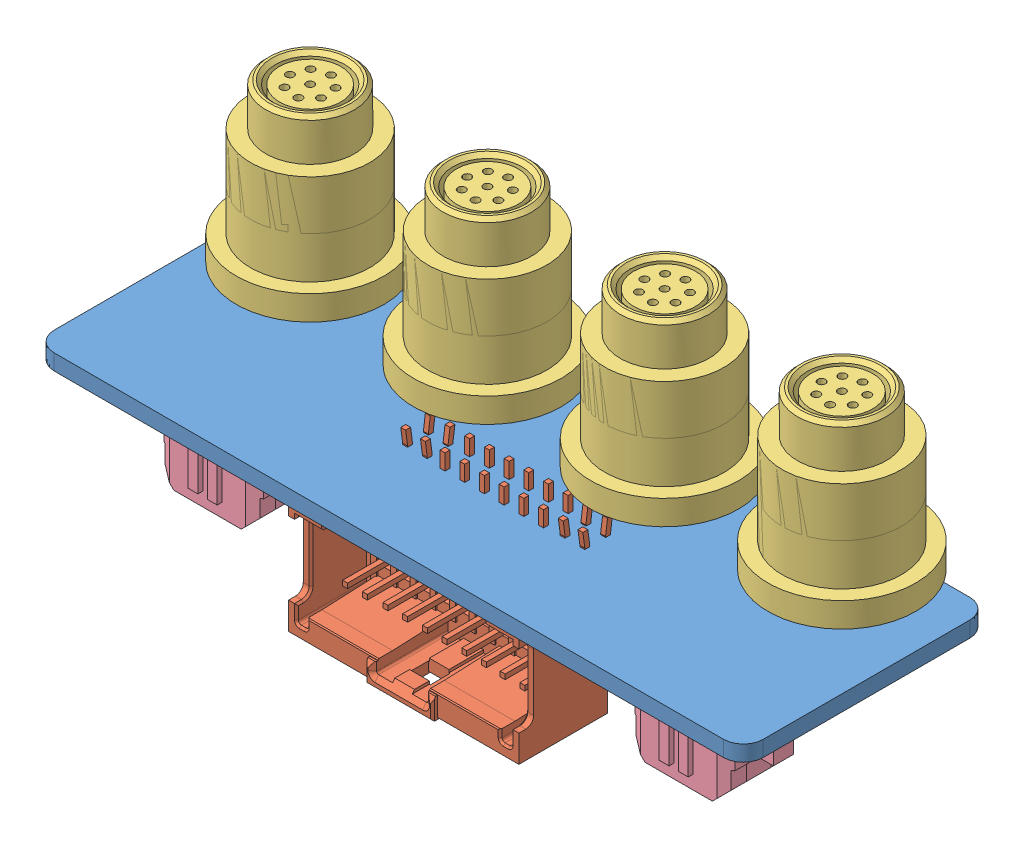
SolidWorks assembly Rear_MCN_BO, configuration Default. Lengths in mm.
Overall size (74.76 32.3 28.38).
8 component instances, 4 part files, 17 mates.
Components (placement in the parent):
- Rear_MCN_BO_PCB-1: Rear_MCN_BO_PCB [Default] at origin size (72 1.6 25)
- MicroClasp_20_RA-1: MicroClasp_20_RA [Default] at (37 -5.05 -7.5) x (-1 0 0) z (0 1 0) size (23.4 14.5 14.9)
- M8 Connector-1: M8 Connector [Default] at (10 20.6 -18) x (-0.837169 0 -0.546944) z (-0.546944 0 0.837169) size (15 22 15)
- M8 Connector-2: M8 Connector [Default] at (28 20.6 -18) x (-0.837169 0 -0.546944) z (-0.546944 0 0.837169) size (15 22 15)
- M8 Connector-3: M8 Connector [Default] at (46 20.6 -18) x (-0.837169 0 -0.546944) z (-0.546944 0 0.837169) size (15 22 15)
- M8 Connector-4: M8 Connector [Default] at (64 20.6 -18) x (-0.837169 0 -0.546944) z (-0.546944 0 0.837169) size (15 22 15)
- Molex MicroFit 4pos vertical header - 43045-0418-1: Molex MicroFit 4pos vertical header - 43045-0418 [Default] at (12.075 -4.96 -8.93) x (-1 0 0) z (0 -1 0) size (13.65 11.2 9.96)
- Molex MicroFit 4pos vertical header - 43045-0418-2: Molex MicroFit 4pos vertical header - 43045-0418 [Default] at (59.925 -4.96 -8.93) x (-1 0 0) z (0 -1 0) size (13.65 11.2 9.96)
Mates (geometry in assembly coordinates):
- Coincident1: coincident anti-aligned: plane of Rear_MCN_BO_PCB-1 through (0 0 0) normal (0 -1 0); plane of MicroClasp_20_RA-1 through (48.7 0 -0.5) normal (0 1 0)
- Coincident2: coincident aligned: plane of Rear_MCN_BO_PCB-1 through (0 1.6 0) normal (0 0 1); plane of MicroClasp_20_RA-1 through (40.425 -11.7 0) normal (0 0 1)
- Distance1: distance = 23.3 mm aligned: plane of MicroClasp_20_RA-1 through (48.7 -5.05 -7.5) normal (1 0 0); plane of Rear_MCN_BO_PCB-1 through (72 1.6 0) normal (1 0 0)
- Coincident3: coincident: plane of Rear_MCN_BO_PCB-1 through (0 1.6 0) normal (0 1 0); plane of M8 Connector-1 through (11.3056 1.6 -16.6473) normal (0 -1 0)
- Coincident4: coincident: plane of Rear_MCN_BO_PCB-1 through (0 1.6 0) normal (0 1 0); plane of M8 Connector-2 through (29.3056 1.6 -16.6473) normal (0 -1 0)
- Coincident5: coincident: plane of Rear_MCN_BO_PCB-1 through (0 1.6 0) normal (0 1 0); plane of M8 Connector-3 through (47.8716 1.6 -18.1774) normal (0 -1 0)
- Coincident6: coincident: plane of Rear_MCN_BO_PCB-1 through (0 1.6 0) normal (0 1 0); plane of M8 Connector-4 through (65.8716 1.6 -18.1774) normal (0 -1 0)
- Concentric3: concentric aligned: circle of Rear_MCN_BO_PCB-1; circle of M8 Connector-1
- Concentric4: concentric aligned: circle of Rear_MCN_BO_PCB-1; circle of M8 Connector-2
- Concentric5: concentric aligned: circle of Rear_MCN_BO_PCB-1; circle of M8 Connector-3
- Concentric6: concentric aligned: circle of Rear_MCN_BO_PCB-1; circle of M8 Connector-4
- Coincident9: coincident: plane of Rear_MCN_BO_PCB-1 through (0 0 0) normal (0 -1 0); plane of Molex MicroFit 4pos vertical header - 43045-0418-2 through (64.75 0 -5) normal (0 1 0)
- Coincident10: coincident: plane of Rear_MCN_BO_PCB-1 through (0 0 0) normal (0 -1 0); plane of Molex MicroFit 4pos vertical header - 43045-0418-1 through (16.9 0 -5) normal (0 1 0)
- Distance2: distance = 5.5 mm: plane of Molex MicroFit 4pos vertical header - 43045-0418-1 through (16.9 -9.91 -5.5) normal (0 0 1); plane of Rear_MCN_BO_PCB-1 through (0 1.6 0) normal (0 0 1)
- Distance3: distance = 7 mm aligned: plane of Molex MicroFit 4pos vertical header - 43045-0418-1 through (7 -4.96 -8.93) normal (-1 0 0); plane of Rear_MCN_BO_PCB-1 through (0 1.6 0) normal (-1 0 0)
- Distance4: distance = 5.5 mm: plane of Rear_MCN_BO_PCB-1 through (0 1.6 0) normal (0 0 1); plane of Molex MicroFit 4pos vertical header - 43045-0418-2 through (64.75 -9.91 -5.5) normal (0 0 1)
- Distance5: distance = 7 mm aligned: plane of Molex MicroFit 4pos vertical header - 43045-0418-2 through (65 -4.96 -8.93) normal (1 0 0); plane of Rear_MCN_BO_PCB-1 through (72 1.6 0) normal (1 0 0)
